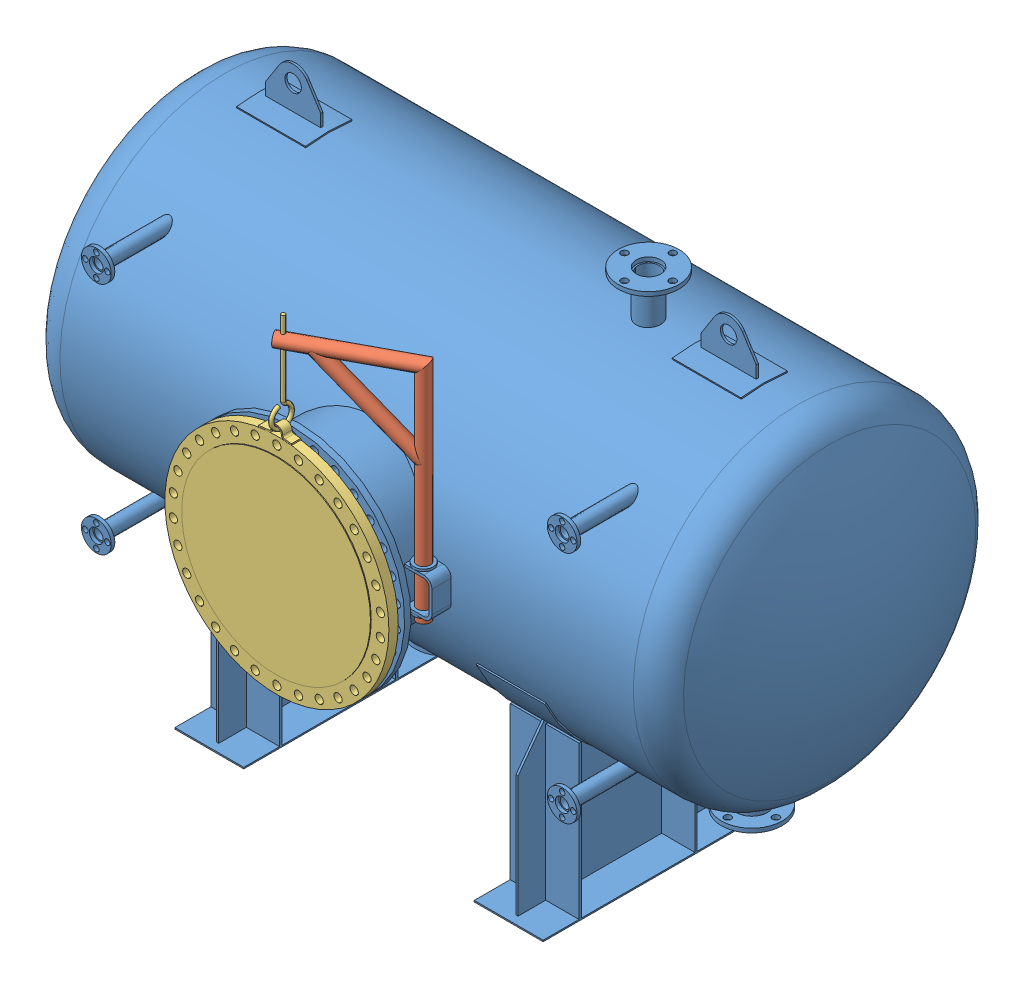
SolidWorks assembly pressure vessel, configuration Default. Lengths in mm.
Overall size (2550.13 1775.36 1480.02).
3 component instances, 3 part files, 7 mates.
Components (placement in the parent):
- body-1: body [Default] at origin size (2550.13 1756.5 1400.3)
- lifting support-1: lifting support [Default] at (331.7558 -103 652.3) x (0.881532 0 -0.472124) z (0.472124 0 0.881532) size (424 822 48)
- manhole cover-1: manhole cover [Default] at (0 0 855.9979) x (0 0 1) z (-1 0 0) size (88.04 1183.76 812.8)
Mates (geometry in assembly coordinates):
- Concentric1: concentric anti-aligned: cylinder of body-1 through (1263.0782 78 652.3) axis (0 -1 0) radius 24; cylinder of lifting support-1 through (1263.0782 -103 652.3) axis (0 1 0) radius 24
- Distance1: distance = 25 mm aligned: plane of body-1 through (331.7558 -78 652.3) normal (0 -1 0); plane of lifting support-1 through (331.7558 -103 652.3) normal (0 -1 0)
- Concentric2: concentric anti-aligned: cylinder of lifting support-1 through (931.3223 719 829.9791) axis (0 -1 0) radius 7; cylinder of manhole cover-1 through (931.3223 505.0428 829.9791) axis (0 1 0) radius 7
- Concentric3: concentric anti-aligned: cylinder of body-1 through (931.3223 0 0) axis (0 0 -1) radius 406.3; cylinder of manhole cover-1 through (931.3223 0 855.9979) axis (0 0 1) radius 406.4
- Coincident4: coincident aligned: plane of body-1 through (0 0 0) normal (0 0 1)
- Coincident5: coincident aligned: plane of body-1 through (0 0 0) normal (0 1 0)
- Coincident6: coincident aligned: plane of body-1 through (0 0 0) normal (1 0 0)
